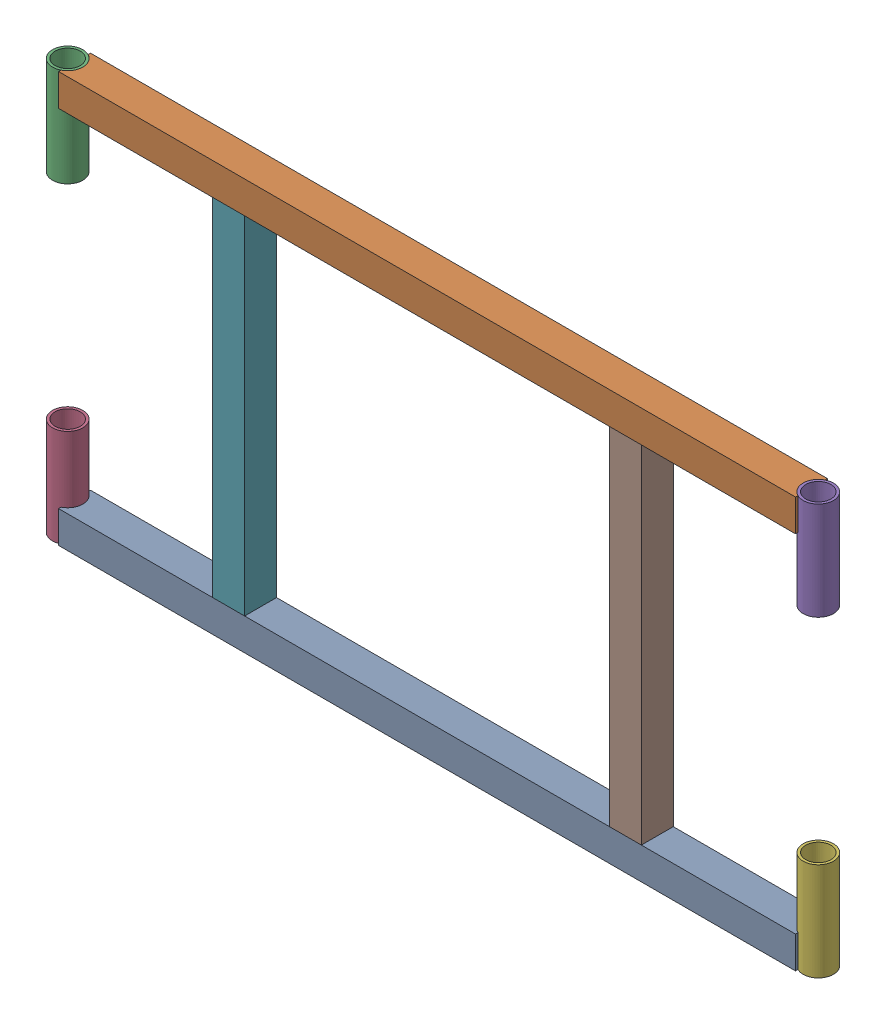
SolidWorks assembly GE-22342, configuration Default. Lengths in mm.
Overall size (1087.37 571.5 44.45).
8 component instances, 3 part files, 20 mates.
Components (placement in the parent):
- GE-22342-01-1: GE-22342-01 [Default] at (0 0 -22.225) size (1026.16 44.45 44.45)
- GE-22342-01-2: GE-22342-01 [Default] at (0 527.05 -22.225) size (1026.16 44.45 44.45)
- GE-22342-03-1: GE-22342-03 [Default] at (-522.605 434.975 -22.225) size (42.16 136.53 42.16)
- GE-22342-03-2: GE-22342-03 [Default] at (-522.605 0 -22.225) size (42.16 136.53 42.16)
- GE-22342-03-3: GE-22342-03 [Default] at (522.605 434.975 -22.225) size (42.16 136.53 42.16)
- GE-22342-03-4: GE-22342-03 [Default] at (522.605 0 -22.225) size (42.16 136.53 42.16)
- GE-22342-02-1: GE-22342-02 [Default] at (-298.45 44.45 0) size (44.45 482.6 44.45)
- GE-22342-02-2: GE-22342-02 [Default] at (254 44.45 0) size (44.45 482.6 44.45)
Mates (geometry in assembly coordinates):
- Coincident1: coincident anti-aligned: plane of fenderHorizontal_mockV2-1 through (0 44.45 -22.225) normal (0 1 0); plane of fenderVertical_mockV2-1 through (-298.45 44.45 0) normal (0 -1 0)
- Coincident2: coincident aligned: plane of fenderHorizontal_mockV2-1 through (0 44.45 0) normal (0 0 1); plane of fenderVertical_mockV2-1 through (-298.45 527.05 0) normal (0 0 1)
- Coincident3: coincident aligned: plane of fenderHorizontal_mockV2-1 through (0 44.45 0) normal (0 0 1); plane of fenderVertical_mockV2-2 through (254 527.05 0) normal (0 0 1)
- Coincident4: coincident anti-aligned: plane of fenderHorizontal_mockV2-1 through (0 44.45 -22.225) normal (0 1 0); plane of fenderVertical_mockV2-2 through (254 44.45 0) normal (0 -1 0)
- Concentric1: concentric aligned: cylinder of fenderHorizontal_mockV2-1 through (522.605 44.45 -22.225) axis (0 -1 0) radius 21.082; cylinder of fenderReceiverPipe_mockV2-4 through (522.605 136.525 -22.225) axis (0 -1 0) radius 21.082
- Coincident5: coincident aligned: plane of fenderHorizontal_mockV2-1 through (0 0 -22.225) normal (0 -1 0); plane of fenderReceiverPipe_mockV2-4 through (522.605 0 -22.225) normal (0 -1 0)
- Concentric2: concentric aligned: cylinder of fenderHorizontal_mockV2-2 through (522.605 571.5 -22.225) axis (0 -1 0) radius 21.082; cylinder of fenderReceiverPipe_mockV2-3 through (522.605 571.5 -22.225) axis (0 -1 0) radius 21.082
- Coincident6: coincident aligned: plane of fenderHorizontal_mockV2-2 through (0 571.5 -22.225) normal (0 1 0); plane of fenderReceiverPipe_mockV2-3 through (522.605 571.5 -22.225) normal (0 1 0)
- Concentric3: concentric aligned: cylinder of fenderHorizontal_mockV2-1 through (-522.605 44.45 -22.225) axis (0 -1 0) radius 21.082; cylinder of fenderReceiverPipe_mockV2-2 through (-522.605 136.525 -22.225) axis (0 -1 0) radius 21.082
- Coincident7: coincident aligned: plane of fenderHorizontal_mockV2-1 through (0 0 -22.225) normal (0 -1 0); plane of fenderReceiverPipe_mockV2-2 through (-522.605 0 -22.225) normal (0 -1 0)
- Concentric4: concentric aligned: cylinder of fenderHorizontal_mockV2-2 through (-522.605 571.5 -22.225) axis (0 -1 0) radius 21.082; cylinder of fenderReceiverPipe_mockV2-1 through (-522.605 571.5 -22.225) axis (0 -1 0) radius 21.082
- Coincident8: coincident aligned: plane of fenderHorizontal_mockV2-2 through (0 571.5 -22.225) normal (0 1 0); plane of fenderReceiverPipe_mockV2-1 through (-522.605 571.5 -22.225) normal (0 1 0)
- Coincident9: coincident anti-aligned: plane of fenderHorizontal_mockV2-2 through (0 527.05 -22.225) normal (0 -1 0); plane of fenderVertical_mockV2-1 through (-298.45 527.05 0) normal (0 1 0)
- Coincident10: coincident aligned: plane of fenderHorizontal_mockV2-2 through (0 571.5 0) normal (0 0 1); plane of fenderVertical_mockV2-1 through (-298.45 527.05 0) normal (0 0 1)
- Coincident11: coincident aligned: plane of fenderHorizontal_mockV2-1 through (513.08 44.45 -22.225) normal (1 0 0); plane of fenderHorizontal_mockV2-2 through (513.08 571.5 -22.225) normal (1 0 0)
- Coincident12: coincident aligned: plane of fenderHorizontal_mockV2-1 through (0 44.45 0) normal (0 0 1)
- Symmetric1: symmetric aligned: plane of fenderHorizontal_mockV2-1 through (513.08 44.45 -22.225) normal (1 0 0); plane of fenderHorizontal_mockV2-1 through (-513.08 44.45 -22.225) normal (-1 0 0)
- Coincident13: coincident anti-aligned: plane of fenderHorizontal_mockV2-1 through (0 0 -22.225) normal (0 -1 0)
- Symmetric2: symmetric aligned: plane of fenderVertical_mockV2-1 through (-254 527.05 0) normal (1 0 0); plane of fenderVertical_mockV2-2 through (254 527.05 0) normal (-1 0 0)
- Distance1: distance = 508 mm anti-aligned: plane of fenderVertical_mockV2-1 through (-254 527.05 0) normal (1 0 0); plane of fenderVertical_mockV2-2 through (254 527.05 0) normal (-1 0 0)
